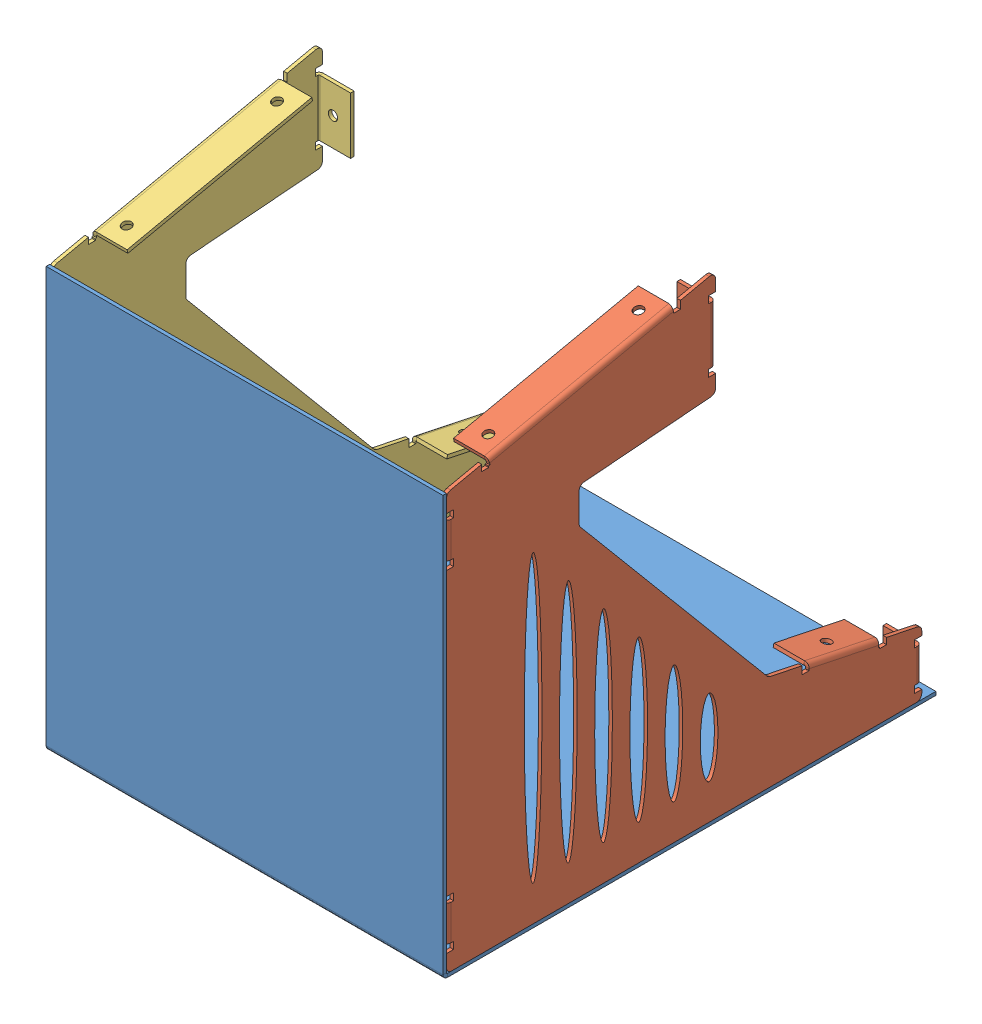
SolidWorks assembly Arcade Cabinet Drive Station, configuration Default. Lengths in mm.
Overall size (286.77 349.08 355.6).
3 component instances, 3 part files, 15 mates.
Components (placement in the parent):
- Back Panel-1: Back Panel [Default] at (118.8655 215.4099 522.8428) size (286.26 302.77 355.6)
- Side Panel Left-1: Side Panel Left [Default] at (261.9945 236.2379 348.8528) size (25.66 340.98 342.9)
- Side Panel Right 2.0-1: Side Panel Right 2.0 [Default] at (-21.7235 236.2379 348.8528) size (41.74 346.54 342.9)
Mates (geometry in assembly coordinates):
- Coincident1: coincident anti-aligned: plane of ? through (4.6382 16.9993 516.0688) normal (0 0 1); plane of Back Panel-1 through (147.7672 5.9577 516.0688) normal (0 0 -1)
- Coincident2: coincident anti-aligned: plane of ? through (288.3562 16.9993 516.0688) normal (0 0 1); plane of Back Panel-1 through (147.7672 167.1133 516.0688) normal (0 0 -1)
- Coincident3: coincident aligned: plane of ? through (290.8962 187.9413 338.2688) normal (1 0 0); plane of Back Panel-1 through (290.8962 16.9993 516.0688) normal (1 0 0)
- Coincident4: coincident aligned: plane of ? through (4.6382 187.9413 338.2688) normal (-1 0 0); plane of Back Panel-1 through (4.6382 -144.1563 516.0688) normal (-1 0 0)
- Coincident6: coincident: line of ? through (7.1782 317.2273 516.0688) axis (-1 0 0); plane of Back Panel-1 through (4.6382 317.2273 516.0688) normal (0 1 0)
- Coincident7: coincident aligned: line of ? through (290.8962 317.2273 516.0688) axis (-1 0 0); line of Back Panel-1 through (290.8962 317.2273 516.0688) axis (-1 0 0)
- Coincident8: coincident aligned: plane of Side Panel Left-1 through (186.3465 196.8014 651.9588) normal (0 0 1); plane of ? through (-97.3715 196.8014 651.9588) normal (0 0 1)
- Coincident9: coincident aligned: plane of Side Panel Left-1 through (160.9465 308.3074 651.9588) normal (0 1 0); plane of ? through (-74.5115 308.3074 651.9588) normal (0 1 0)
- Coincident10: coincident anti-aligned: plane of Back Panel-1 through (98.093 215.4099 511.1832) normal (0 0 -1); plane of Side Panel Left-1 through (241.222 236.2379 511.1832) normal (0 0 1)
- Coincident11: coincident aligned: plane of Back Panel-1 through (241.222 65.2959 511.1832) normal (1 0 0); plane of Side Panel Left-1 through (241.222 236.2379 339.7332) normal (1 0 0)
- Coincident13: coincident aligned: plane of Back Panel-1 through (-99.9115 25.8594 651.9588) normal (-1 0 0); plane of ? through (-99.9115 196.8014 474.1588) normal (-1 0 0)
- Coincident14: coincident aligned: line of Back Panel-1 through (241.222 65.2959 510.4466) axis (0 0 -1); line of Side Panel Left-1 through (241.222 65.2959 507.3732) axis (0 0 -1)
- Coincident15: coincident: plane of Back Panel-1 through (-24.2635 62.7559 520.3028) normal (-1 0 0); plane of Side Panel Right 2.0-1 through (-24.2635 280.6313 348.8528) normal (-1 0 0)
- Coincident16: coincident: plane of Back Panel-1 through (118.8655 215.4099 520.3028) normal (0 0 -1); plane of Side Panel Right 2.0-1 through (-21.7235 280.6313 520.3028) normal (0 0 1)
- Coincident17: coincident anti-aligned: plane of Back Panel-1 through (118.8655 65.2959 522.8428) normal (0 1 0); plane of Side Panel Right 2.0-1 through (-24.2635 65.2959 520.3028) normal (0 -1 0)
